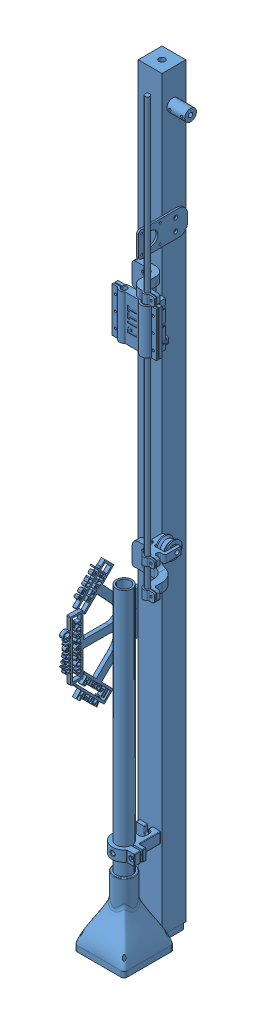
SolidWorks assembly Complete Assembly, configuration Default. Lengths in mm.
Overall size (122.05 1263.57 165.67).
3 component instances, 3 part files, 6 mates.
Components (placement in the parent):
- Fan to Hose Funnel Rev 2-1: Fan to Hose Funnel Rev 2 [Default] at (210.9455 224.6996 1402.8006) size (122.05 1263.57 165.67)
- Fipple Motor Tab-1: Fipple Motor Tab [Default] at (212.1664 204.9996 1400.4864) x (0.997951 0 -0.063978) z (0.063978 0 0.997951) size (51.58 5 16) (hidden)
- PVC Holder-1: PVC Holder [Default] at (210.9455 206.6996 1402.8006) size (83.37 18 53.07) (hidden)
Mates (geometry in assembly coordinates):
- Concentric1: concentric aligned: cylinder of Fan to Hose Funnel Rev 2-1 through (210.9455 747.3046 1402.8006) axis (0 -1 0) radius 13.375; cylinder of PVC Holder-1 through (210.9455 356.7796 1402.8006) axis (0 -1 0) radius 13.5
- Coincident1: coincident anti-aligned: plane of Fan to Hose Funnel Rev 2-1 through (210.9455 356.7796 1402.8006) normal (0 -1 0); plane of PVC Holder-1 through (210.9455 356.7796 1402.8006) normal (0 1 0)
- Distance2: distance = 12.7 mm anti-aligned: plane of Fipple Motor Tab-1 through (212.1664 326.0796 1400.4864) normal (0 1 0); plane of PVC Holder-1 through (210.9455 338.7796 1402.8006) normal (0 -1 0)
- Coincident3: coincident: axis of Fipple Motor Tab-1 through (173.8598 322.0796 1382.6301) axis (0 1 0); plane of assembly
- Coincident4: coincident: axis of Fipple Motor Tab-1 through (173.8598 322.0796 1382.6301) axis (0 1 0); plane of assembly
- Parallel2: parallel aligned: plane of Fan to Hose Funnel Rev 2-1 through (230.9455 1477.6996 1359.2131) normal (0 0 1); plane of PVC Holder-1 through (210.9455 353.7796 1397.6801) normal (0 0 1)
